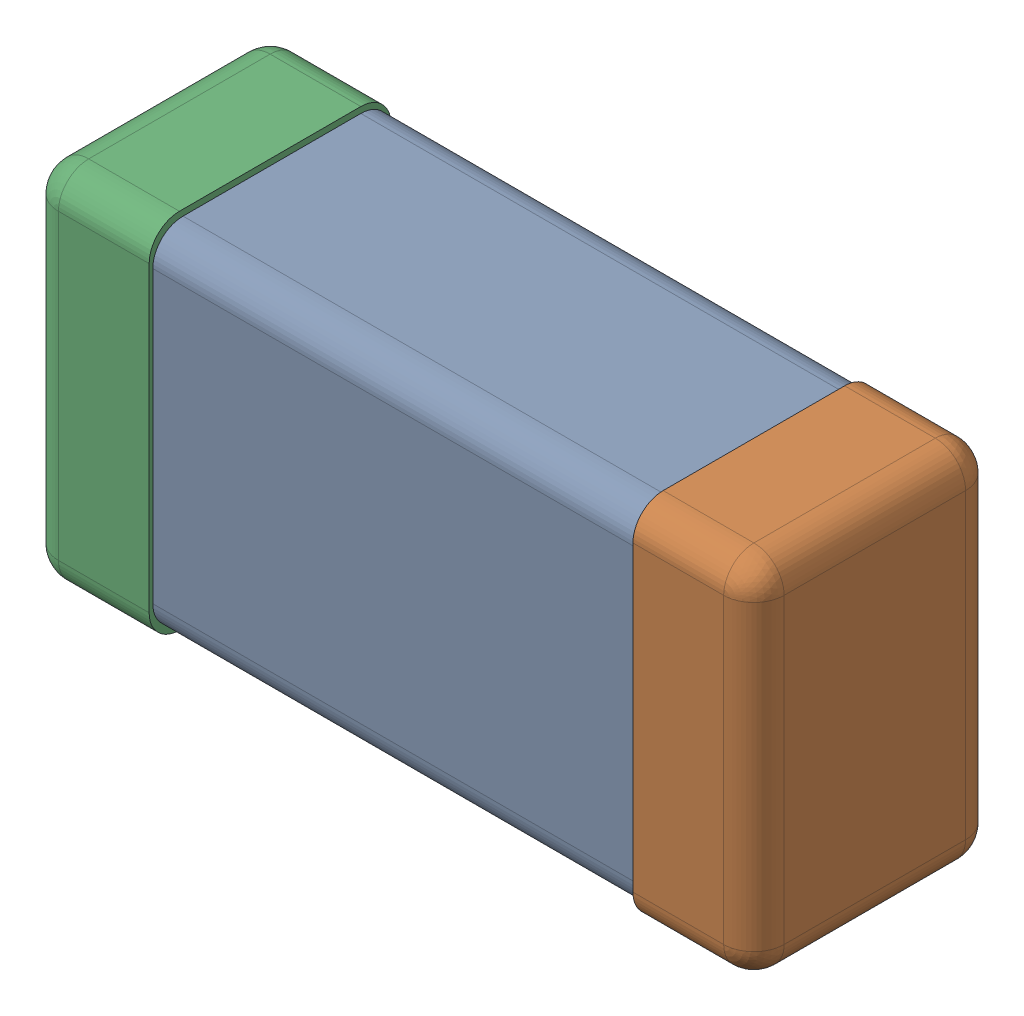
SolidWorks assembly C0201_020_6, configuration Standard. Lengths in mm.
Overall size (0.6 0.3 0.2).
4 component instances, 3 part files, 0 mates.
Components (placement in the parent):
- C0201_020_7-1: C0201_020_7 [Standard] at origin size (0.6 0.3 0.2)
  - Part 3_2-1: Part 3_2 [Standard] at (0 0 -7.3015) size (0.5 0.29 0.2)
  - Part 2_2-1: Part 2_2 [Standard] at (0 0 -7.3) size (0.1 0.3 0.2)
  - Part 1_2-1: Part 1_2 [Standard] at (0 0 -7.3) size (0.1 0.3 0.2)
